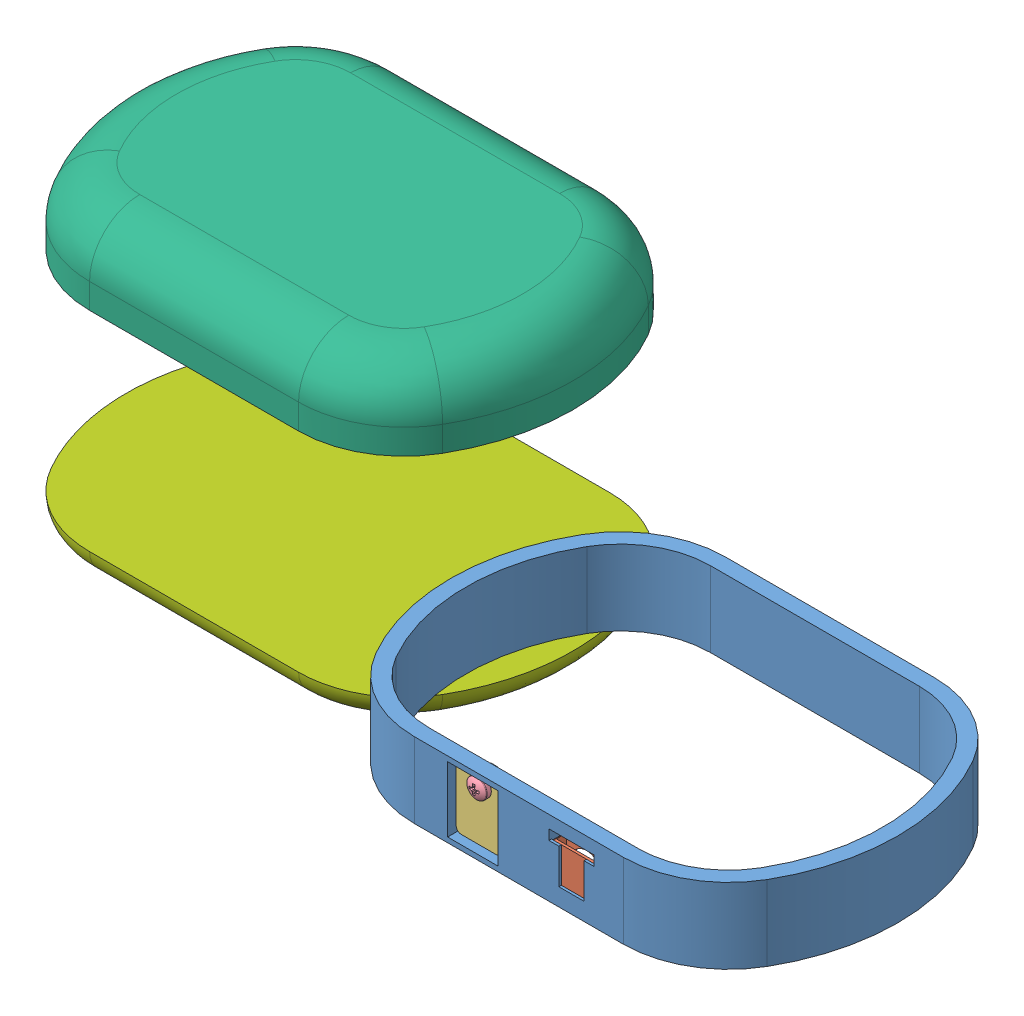
SolidWorks assembly Projekt, configuration 默认. Lengths in mm.
Overall size (193.4 61.61 101.7).
7 component instances, 7 part files, 16 mates.
Components (placement in the parent):
- halterung-1: halterung [默认] at (156.5963 30.1284 60.4158) size (89 15 62)
- Venti-1: Venti [默认] at (157.5724 35.8443 98.2047) x (0 1 0) z (0 0 1) size (9.71 9.71 3)
- Lighgt-1: Lighgt [默认] at (140.4933 37.877 99.2047) size (10 13 5.8)
- pan head cross recess screw_din-1: pan head cross recess screw_din [DIN EN ISO 7045 - M2 x 3 - Z - 3N] at (139.7258 41.6284 101.6047) x (0 0 -1) z (-0.999968 -0.00794 0) size (4.57 4 4)
- hex nut style 1 gradeab_din-1: hex nut style 1 gradeab_din [Hexagon Nut ISO 4032 - M2 - W - N] at (139.7258 41.6284 97.1047) x (0.923728 0.383049 0) z (0 0 -1) size (4 4.62 1.6)
- Case 1-1: Case 1 [默认] at (52.2 46.6147 20.7111) size (89 15 62)
- Case 2-1: Case 2 [默认] at (36.8 5 20.7111) x (-1 0 0) z (0 0 1) size (89 5 62)
Mates (geometry in assembly coordinates):
- 重合4: coincident anti-aligned: plane of halterung-1 through (156.5963 30.1284 101.2047) normal (0 0 -1); plane of Venti-1 through (157.5724 35.8443 101.2047) normal (0 0 1)
- 重合5: coincident anti-aligned: plane of halterung-1 through (154.8963 31.6284 39.7037) normal (0 1 0); plane of Venti-1 through (154.8963 31.6284 101.2047) normal (0 -1 0)
- 重合6: coincident anti-aligned: plane of halterung-1 through (163.8963 31.6284 39.7037) normal (-1 0 0); plane of Venti-1 through (163.8963 31.6284 101.2047) normal (1 0 0)
- 同心2: concentric anti-aligned: cylinder of Lighgt-1 through (139.7258 41.6284 100.0057) axis (0 0 -1) radius 1.25; cylinder of pan head cross recess screw_din-1 through (139.7258 41.6284 127.0047) axis (0 0 1) radius 1
- 重合9: coincident anti-aligned: plane of Lighgt-1 through (143.7258 43.2284 100.0047) normal (0 0 1); plane of pan head cross recess screw_din-1 through (139.7338 40.6284 100.0047) normal (0 0 -1)
- 同心3: concentric anti-aligned: cylinder of pan head cross recess screw_din-1 through (139.7258 41.6284 127.0047) axis (0 0 1) radius 1; cylinder of hex nut style 1 gradeab_din-1 through (139.7258 41.6284 48.9233) axis (0 0 -1) radius 0.8
- 重合14: coincident anti-aligned: plane of Case 2-1 through (36.8 0 20.7111) normal (0 -1 0)
- 重合15: coincident anti-aligned: plane of Case 1-1 through (0 61.6147 0) normal (0 0 -1)
- 相切1: tangent: circle of Case 1-1
- 平行1: parallel anti-aligned: line of Case 1-1 through (23.6795 46.6147 62) axis (1 0 0); line of Case 2-1 through (65.3205 5 62) axis (-1 0 0)
- 平行2: parallel anti-aligned: plane of Case 1-1 through (52.2 46.6147 20.7111) normal (0 -1 0); plane of Case 2-1 through (36.8 5 20.7111) normal (0 1 0)
- 同心4: concentric anti-aligned: circle of Case 1-1; circle of Case 2-1
- 重合25: coincident anti-aligned: plane of halterung-1 through (156.5963 30.1284 99.2047) normal (0 0 1); plane of Lighgt-1 through (143.7258 43.2284 99.2047) normal (0 0 -1)
- 同心5: concentric aligned: cylinder of halterung-1 through (139.7258 41.6284 96.7047) axis (0 0 1) radius 1.25; cylinder of pan head cross recess screw_din-1 through (139.7258 41.6284 127.0047) axis (0 0 1) radius 1
- 平行5: parallel anti-aligned: plane of halterung-1 through (134.7258 31.1284 99.2047) normal (0 1 0); plane of Lighgt-1 through (135.7258 31.2284 100.0047) normal (0 -1 0)
- 重合29: coincident anti-aligned: plane of halterung-1 through (128.0758 30.1274 98.7047) normal (0 0 -1); plane of hex nut style 1 gradeab_din-1 through (140.6104 39.4951 98.7047) normal (0 0 1)
